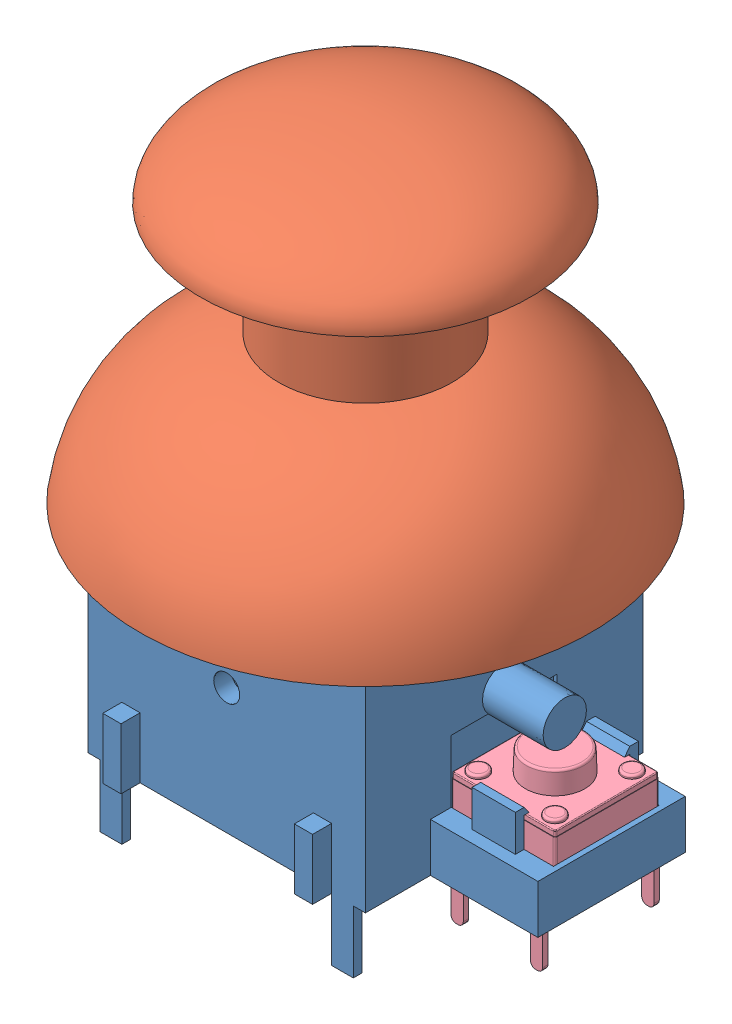
SolidWorks assembly Assemblage2, configuration Défaut. Lengths in mm.
Overall size (27.78 35.1 27.15).
5 component instances, 4 part files, 11 mates.
Components (placement in the parent):
- Mécanisme-1: Mécanisme [Défaut] at (4.6458 -13.2312 -0.55) size (22.2 23.1 17.1)
- Manche-1: Manche [Défaut] at (4.6458 -0.7312 -0.55) x (0.998969 0 -0.045407) z (0.045407 0 0.998969) size (26 19 26)
- Potentiometre-1: Potentiometre [Défaut] at (4.6458 -6.4812 -8.55) x (-1 0 0) z (0 0 -1) size (9.5 14.5 4)
- Potentiometre-2: Potentiometre [Défaut] at (-3.3542 -6.4812 -0.55) x (0 0 1) z (-1 0 0) size (9.5 14.5 4)
- tactileswitch-1: tactileswitch [Default] at (15.5423 -12.4312 -0.5965) x (0 0 -1) z (1 0 0) size (6.72 8.35 6.01)
Mates (geometry in assembly coordinates):
- Coïncidente1: coincident anti-aligned: plane of Mécanisme-1 through (4.6458 -12.4312 -0.55) normal (0 1 0); plane of tactileswitch-1 through (12.5387 -12.4312 -1.8982) normal (0 -1 0)
- Coïncidente2: coincident anti-aligned: plane of Mécanisme-1 through (18.5458 -6.8312 -3.6) normal (0 0 1); plane of tactileswitch-1 through (18.5458 -9.053 -3.6) normal (0 0 -1)
- Coïncidente3: coincident anti-aligned: plane of Mécanisme-1 through (18.5458 -6.8312 2.5) normal (-1 0 0); plane of tactileswitch-1 through (18.5458 -9.053 2.4071) normal (1 0 0)
- Coïncidente4: coincident anti-aligned: plane of Mécanisme-1 through (-3.3542 -1.2312 -8.55) normal (0 0 -1); plane of Potentiometre-1 through (4.6458 -6.4812 -8.55) normal (0 0 1)
- Parallèle1: parallel aligned: plane of Mécanisme-1 through (4.6458 -1.2312 -0.55) normal (0 1 0); plane of Potentiometre-1 through (-0.1042 -0.9812 -11.55) normal (0 1 0)
- Coaxiale1: concentric anti-aligned: circle of Mécanisme-1; circle of Potentiometre-1
- Coïncidente7: coincident anti-aligned: plane of Mécanisme-1 through (-3.3542 -1.2312 7.45) normal (-1 0 0); plane of Potentiometre-2 through (-3.3542 -6.4812 -0.55) normal (1 0 0)
- Coaxiale2: concentric anti-aligned: cylinder of Mécanisme-1 through (16.1458 -5.9812 -0.55) axis (-1 0 0) radius 1.25; cylinder of Potentiometre-2 through (-7.3542 -5.9812 -0.55) axis (1 0 0) radius 2
- Parallèle2: parallel aligned: plane of Mécanisme-1 through (4.6458 -1.2312 -0.55) normal (0 1 0); plane of Potentiometre-2 through (-6.3542 -0.9812 4.2) normal (0 1 0)
- Coaxiale3: concentric: cylinder of Mécanisme-1 through (4.6458 -1.2312 -0.55) axis (0 -1 0) radius 3.5; cylinder of Manche-1 through (4.6458 4.4929 -0.55) axis (0 -1 0) radius 1
- Distance1: distance = 3.5 mm anti-aligned: plane of Manche-1 through (5.6448 2.2688 -0.5954) normal (0 -1 0); plane of Mécanisme-1 through (4.6458 -1.2312 -0.55) normal (0 1 0)
